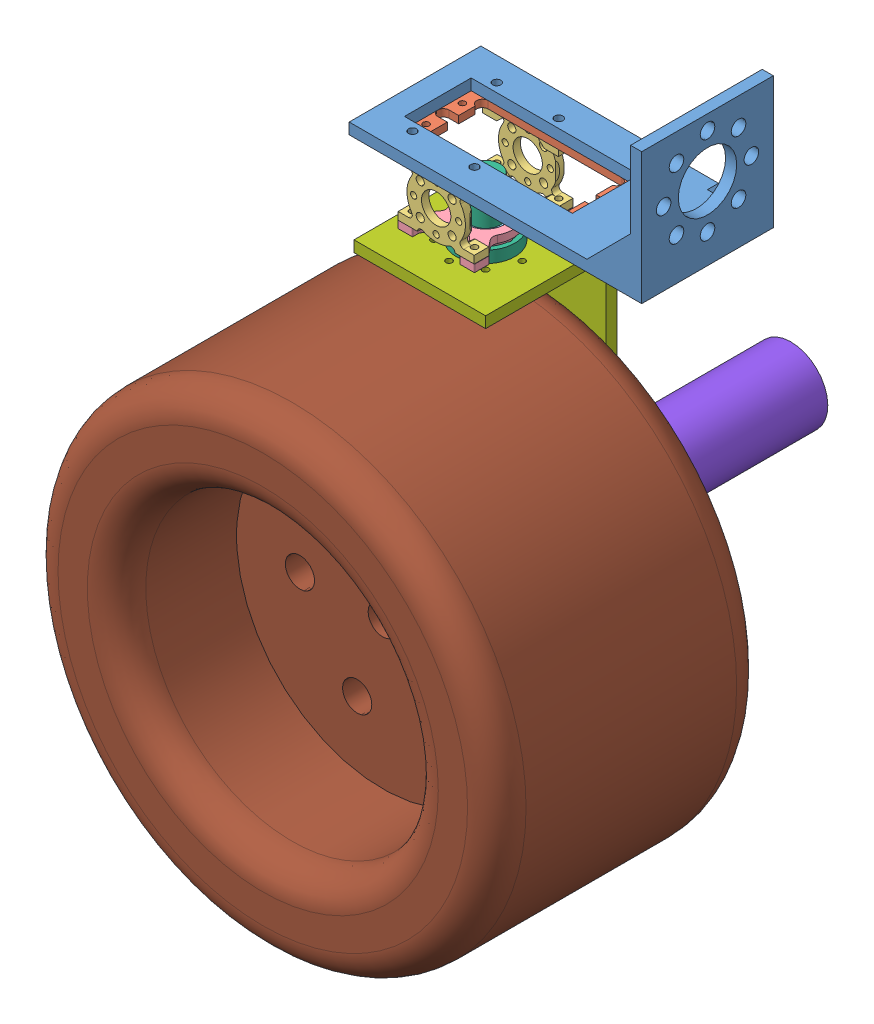
SolidWorks assembly Front_wheel_SUBASSEM, configuration Default. Lengths in mm.
Overall size (203.2 315.88 229.31).
18 component instances, 11 part files, 21 mates.
Components (placement in the parent):
- Servo_base_front-1: Servo_base_front [Default] at (66.9376 47.4067 44.7676) size (127 55.2 57.15)
- servo_mount-1: servo_mount [Default] at (63.4948 44.2317 73.3426) size (79.25 3.17 42.93)
- wheel_hold_left_right-1: wheel_hold_left_right [Default] at (47.8121 31.5317 51.8796) x (0 -1 0) z (-1 0 0) size (25.4 6.35 33.02)
- wheel_hold_left_right-2: wheel_hold_left_right [Default] at (47.8121 31.5317 94.8056) x (0 1 0) z (-1 0 0) size (25.4 6.35 33.02)
- Bearing_mount_subsubass-1: Bearing_mount_subsubass [Default] at (82.6306 37.2877 87.6325) x (0 0 -1) z (-1 0 0) size (42.93 5.08 33.27)
  - 535182-1: 535182 [Default] at (14.2899 18.456 34.8186) size (42.93 5.08 33.27)
  - .5 x .75 non flanged bearing-1: .5 x .75 non flanged bearing [Default] at (14.2899 19.5736 34.8186) x (0.770155 0 0.637857) z (-0.637857 0 0.770155) size (19.05 3.91 19.05)
- Mounting_hub_circular_servo-1: Mounting_hub_circular_servo [Default] at (47.8121 8.9765 73.3426) x (-0.707107 0 -0.707107) z (0.707107 0 -0.707107) size (25.39 25.4 25.39)
- Wheel_extension_sheet-2: Wheel_extension_sheet [Default] at (19.2371 8.9765 101.9176) size (57.15 139.7 57.15)
- Motor_and_mount_subass-1: Motor_and_mount_subass [Default] at (28.0226 -206.4882 -27.8911) x (0.696282 0.717769 0) z (0 0 1) size (46.7 46.7 115)
  - Motors-1: Motors [Default] at (81.834 51.8135 -31.3435) size (32 32 115)
  - Motor_mount-2: Motor_mount [Default] at (45.268 5.1287 35.3702) x (-0.707107 -0.707107 0) z (-0.707107 0.707107 0) size (33.02 8.74 33.02)
    - 555174-1: 555174 [Default] at (-58.8675 33.2863 7.1552) size (33.02 4.05 33.02)
    - 555174 screw_92005A116-1: 555174 screw_92005A116 [Default] at (-68.0596 28.5563 -2.0369) x (1 0 0) z (0 1 0) size (6 6 8.48)
    - 555174 screw_92005A116-2: 555174 screw_92005A116 [Default] at (-68.0596 28.5563 16.3474) x (0 0 -1) z (0 1 0) size (6 6 8.48)
    - 555174 screw_92005A116-3: 555174 screw_92005A116 [Default] at (-49.6753 28.5563 16.3474) x (-1 0 0) z (0 1 0) size (6 6 8.48)
    - 555174 screw_92005A116-4: 555174 screw_92005A116 [Default] at (-49.6753 28.5563 -2.0369) x (0 0 1) z (0 1 0) size (6 6 8.48)
- wheel_exa_1-1: wheel_exa_1 [Default] at (47.8121 -111.6735 55.7793) size (203.2 203.2 116.84)
Mates (geometry in assembly coordinates):
- Concentric1: concentric anti-aligned: cylinder of Servo_base_front-1 through (61.2824 47.4067 91.6306) axis (0 1 0) radius 1.778; cylinder of servo_mount-1 through (61.2824 47.4067 91.6306) axis (0 -1 0) radius 1.778
- Concentric2: concentric anti-aligned: cylinder of Servo_base_front-1 through (34.3417 47.4067 91.6306) axis (0 1 0) radius 1.778; cylinder of servo_mount-1 through (34.3417 47.4067 91.6306) axis (0 -1 0) radius 1.778
- Concentric3: concentric anti-aligned: cylinder of Servo_base_front-1 through (61.2824 47.4067 55.0546) axis (0 1 0) radius 1.778; cylinder of servo_mount-1 through (61.2824 47.4067 55.0546) axis (0 -1 0) radius 1.778
- Coincident1: coincident anti-aligned: plane of Servo_base_front-1 through (17.1576 47.4067 101.9176) normal (0 -1 0); plane of servo_mount-1 through (55.8849 47.4067 54.1021) normal (0 1 0)
- Concentric4: concentric aligned: cylinder of servo_mount-1 through (61.2824 47.4067 55.0546) axis (0 -1 0) radius 1.778; cylinder of wheel_hold_left_right-1 through (61.2824 40.938 55.0546) axis (0 -1 0) radius 1.3526
- Concentric5: concentric anti-aligned: cylinder of servo_mount-1 through (34.3417 47.4067 55.0546) axis (0 -1 0) radius 1.778; cylinder of wheel_hold_left_right-1 through (34.3417 44.2317 55.0546) axis (0 1 0) radius 1.3526
- Coincident2: coincident anti-aligned: plane of servo_mount-1 through (55.8849 44.2317 54.1021) normal (0 -1 0); plane of wheel_hold_left_right-1 through (47.8121 44.2317 39.7407) normal (0 1 0)
- Concentric6: concentric aligned: cylinder of servo_mount-1 through (34.3417 47.4067 91.6306) axis (0 -1 0) radius 1.778; cylinder of wheel_hold_left_right-2 through (34.3417 40.938 91.6306) axis (0 -1 0) radius 1.3526
- Concentric7: concentric anti-aligned: cylinder of servo_mount-1 through (61.2824 47.4067 91.6306) axis (0 -1 0) radius 1.778; cylinder of wheel_hold_left_right-2 through (61.2824 44.2317 91.6306) axis (0 1 0) radius 1.3526
- Coincident3: coincident anti-aligned: plane of servo_mount-1 through (55.8849 44.2317 54.1021) normal (0 -1 0); plane of wheel_hold_left_right-2 through (47.8121 44.2317 106.9446) normal (0 1 0)
- Concentric8: concentric anti-aligned: circle of wheel_hold_left_right-1; cylinder of Bearing_mount_subsubass-1/535182-1 through (34.3417 15.6567 55.0546) axis (0 -1 0) radius 1.778
- Concentric9: concentric aligned: cylinder of wheel_hold_left_right-2 through (34.3417 18.8317 91.6306) axis (0 -1 0) radius 1.3526; cylinder of Bearing_mount_subsubass-1/535182-1 through (34.3417 15.6567 91.6306) axis (0 -1 0) radius 1.778
- Coincident4: coincident anti-aligned: plane of wheel_hold_left_right-1 through (47.8121 18.8317 39.7407) normal (0 -1 0); plane of Bearing_mount_subsubass-1/535182-1 through (47.8121 18.8317 73.3426) normal (0 1 0)
- Concentric10: concentric anti-aligned: cylinder of Bearing_mount_subsubass-1/.5 x .75 non flanged bearing-1 through (47.8121 13.8025 73.3426) axis (0 1 0) radius 6.35; cylinder of Mounting_hub_circular_servo-1 through (47.8121 34.3765 73.3426) axis (0 -1 0) radius 6.3462
- Coincident5: coincident anti-aligned: plane of Bearing_mount_subsubass-1/.5 x .75 non flanged bearing-1 through (47.8121 14.0565 73.3426) normal (0 -1 0); plane of Mounting_hub_circular_servo-1 through (38.8345 14.0565 64.3651) normal (0 1 0)
- Parallel2: parallel aligned: line of Servo_base_front-1 through (119.0858 52.2327 44.7676) axis (-1 0 0); line of Wheel_extension_sheet-2 through (76.3871 8.9765 44.7676) axis (-1 0 0)
- Concentric27: concentric aligned: circle of Wheel_extension_sheet-2; cylinder of Motor_and_mount_subass-1/Motors-1 through (47.8121 -111.6735 55.7655) axis (0 0 -1) radius 3
- Concentric28: concentric aligned: cylinder of Mounting_hub_circular_servo-1 through (38.0331 14.0565 73.3426) axis (0 1 0) radius 1.3526; cylinder of Wheel_extension_sheet-2 through (38.0331 8.9765 73.3426) axis (0 1 0) radius 1.3526
- Concentric29: concentric aligned: cylinder of Mounting_hub_circular_servo-1 through (57.5911 14.0565 73.3426) axis (0 1 0) radius 1.3526; cylinder of Wheel_extension_sheet-2 through (57.5911 8.9765 73.3426) axis (0 1 0) radius 1.3526
- Coincident6: coincident anti-aligned: plane of Mounting_hub_circular_servo-1 through (47.8121 8.9765 73.3426) normal (0 -1 0); plane of Wheel_extension_sheet-2 through (76.3871 8.9765 101.9176) normal (0 1 0)
- Concentric30: concentric anti-aligned: cylinder of Motor_and_mount_subass-1/Motors-1 through (47.8121 -111.6735 55.7655) axis (0 0 -1) radius 3; cylinder of wheel_exa_1-1 through (47.8121 -111.6735 53.2393) axis (0 0 1) radius 6.35
